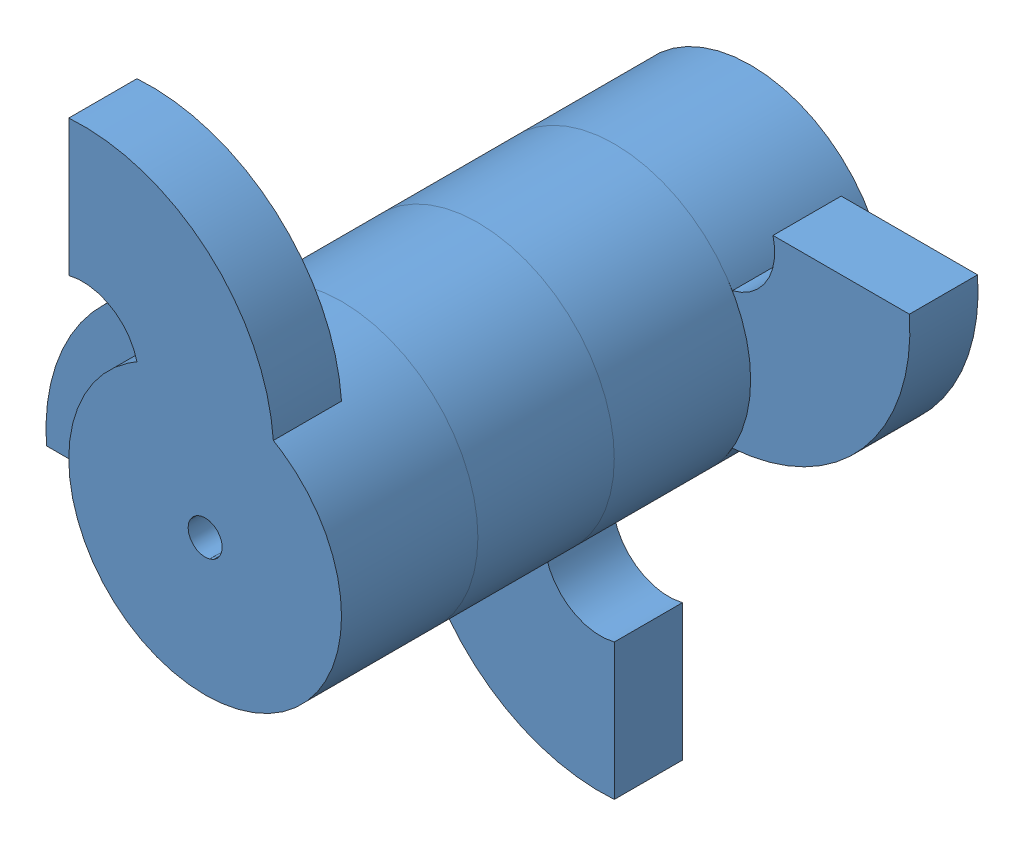
SolidWorks assembly rotator_gauche, configuration Default. Lengths in mm.
Overall size (173.39 173.39 160).
4 component instances, 1 part files, 9 mates.
Components (placement in the parent):
- Part5_gauche-4: Part5_gauche [Default] at (-39.2063 97.1379 61.3675) x (0 1 0) z (0 0 1) size (126.7 80 40)
- Part5_gauche-3: Part5_gauche [Default] at (-45.7554 10.5887 21.3675) x (-1 0 0) z (0 0 1) size (126.7 80 40)
- Part5_gauche-2: Part5_gauche [Default] at (40.7937 4.0396 -18.6325) x (0 -1 0) z (0 0 1) size (126.7 80 40)
- Part5_gauche-1: Part5_gauche [Default] at (47.3428 90.5887 -58.6325) size (126.7 80 40)
Mates (geometry in assembly coordinates):
- Concentric1: concentric aligned: cylinder of Part5_gauche-1 through (0.7937 50.5887 -38.6325) axis (0 0 -1) radius 5; cylinder of Part5_gauche-2 through (0.7937 50.5887 1.3675) axis (0 0 -1) radius 5
- Coincident1: coincident anti-aligned: plane of Part5_gauche-1 through (31.3888 86.5428 -38.6325) normal (0 0 1); plane of Part5_gauche-2 through (0.7937 50.5887 -38.6325) normal (0 0 -1)
- Concentric2: concentric aligned: cylinder of Part5_gauche-2 through (0.7937 50.5887 1.3675) axis (0 0 -1) radius 5; cylinder of Part5_gauche-3 through (0.7937 50.5887 41.3675) axis (0 0 -1) radius 5
- Coincident2: coincident anti-aligned: plane of Part5_gauche-2 through (36.7477 19.9937 1.3675) normal (0 0 1); plane of Part5_gauche-3 through (0.7937 50.5887 1.3675) normal (0 0 -1)
- Concentric3: concentric: cylinder of Part5_gauche-3 through (0.7937 50.5887 41.3675) axis (0 0 -1) radius 5; cylinder of Part5_gauche-4 through (0.7937 50.5887 81.3675) axis (0 0 -1) radius 5
- Coincident3: coincident: plane of Part5_gauche-3 through (-29.8014 14.6347 41.3675) normal (0 0 1); plane of Part5_gauche-4 through (0.7937 50.5887 41.3675) normal (0 0 -1)
- Perpendicular1: perpendicular: line of Part5_gauche-2 through (40.7937 -35.9604 -18.6325) axis (0 1 0); line of Part5_gauche-1 through (87.3428 90.5887 -58.6325) axis (-1 0 0)
- Perpendicular2: perpendicular: line of Part5_gauche-3 through (-85.7554 10.5887 21.3675) axis (1 0 0); line of Part5_gauche-2 through (40.7937 -35.9604 -18.6325) axis (0 1 0)
- Perpendicular3: perpendicular: line of Part5_gauche-4 through (-39.2063 137.1379 61.3675) axis (0 -1 0); line of Part5_gauche-3 through (-85.7554 10.5887 21.3675) axis (1 0 0)
